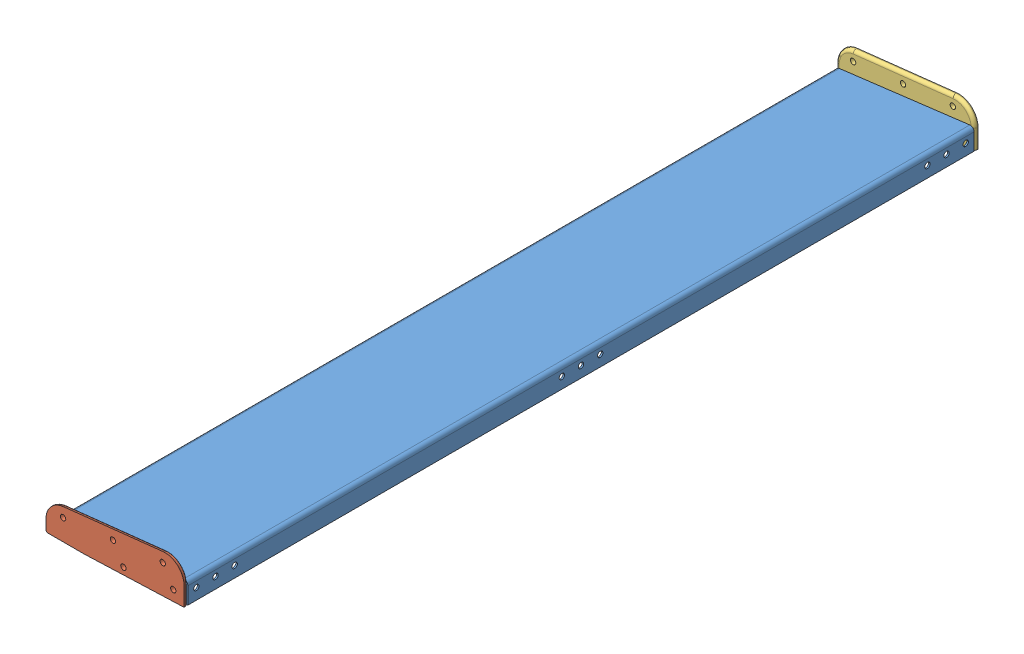
SolidWorks assembly 斜坡板焊接, configuration 默认. Lengths in mm.
Overall size (360 109.38 2070).
7 component instances, 4 part files, 2 mates.
Components (placement in the parent):
- 斜坡板折弯（花纹钢板）-1: 斜坡板折弯（花纹钢板） [默认] at (-433.4532 1575.2553 1025) size (360 63.67 2050)
- 斜坡板安装板-1: 斜坡板安装板 [默认] at origin size (360 108.63 10)
- 斜坡板安装板2-1: 斜坡板安装板2 [默认] at (0 0 -2040) size (360 109.25 10)
- 零件13^斜坡板焊接-1: 零件13^斜坡板焊接 [默认] at origin size (352 56.27 6) (virtual)
- 零件13^斜坡板焊接-2: 零件13^斜坡板焊接 [默认] at (0 0 -200) size (352 56.27 6) (virtual)
- 零件13^斜坡板焊接-3: 零件13^斜坡板焊接 [默认] at (0 0 -1600) size (352 56.27 6) (virtual)
- 零件13^斜坡板焊接-4: 零件13^斜坡板焊接 [默认] at (0 0 -1400) size (352 56.27 6) (virtual)
Mates (geometry in assembly coordinates):
- 重合1: coincident: plane of 斜坡板折弯（花纹钢板）-1 through (-443.4532 1618.9275 1025) normal (0 0 -1); plane of 斜坡板安装板2-1 through (-483.4532 1624.6303 1025) normal (0 0 1)
- 重合3: coincident: plane of 斜坡板安装板2-1 through (-793.4532 1595.3803 1025) normal (-1 0 0); plane of 斜坡板折弯（花纹钢板）-1 through (-793.4532 1576.4275 3075) normal (-1 0 0)
